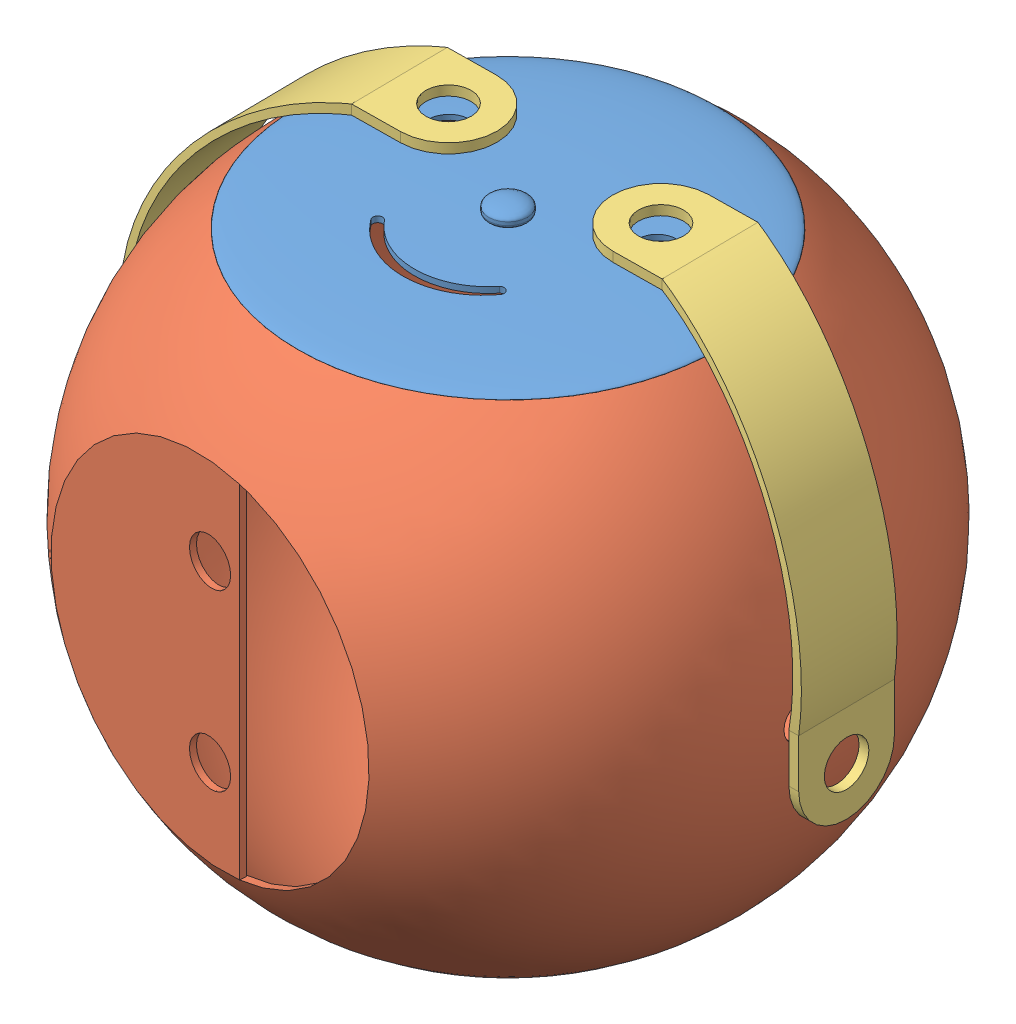
SolidWorks assembly Head, configuration Default. Lengths in mm.
Overall size (216.68 188.6 202.73).
3 component instances, 3 part files, 1 mates.
Components (placement in the parent):
- Part2-1: Part2 [Default] at (19.0461 92.6358 93.1686) size (130 10 130)
- Headshell-1: Headshell [Default] at (19.0461 15.3312 93.1686) x (-0.996419 0 -0.084552) z (0 1 0) size (201.64 186.35 178.3)
- Eyes2-1: Eyes2 [Default] at (19.2177 -0.0714 92.7653) x (0 1 0) z (0.999923 0 -0.012375) size (118 44.77 210.57)
Mates (geometry in assembly coordinates):
- Concentric9: concentric aligned: cylinder of Part2-1 through (-13.4539 100.6368 79.0957) axis (0 -1 0) radius 6; cylinder of Eyes2-1 through (-13.4539 102.9286 79.0957) axis (0 -1 0) radius 7
